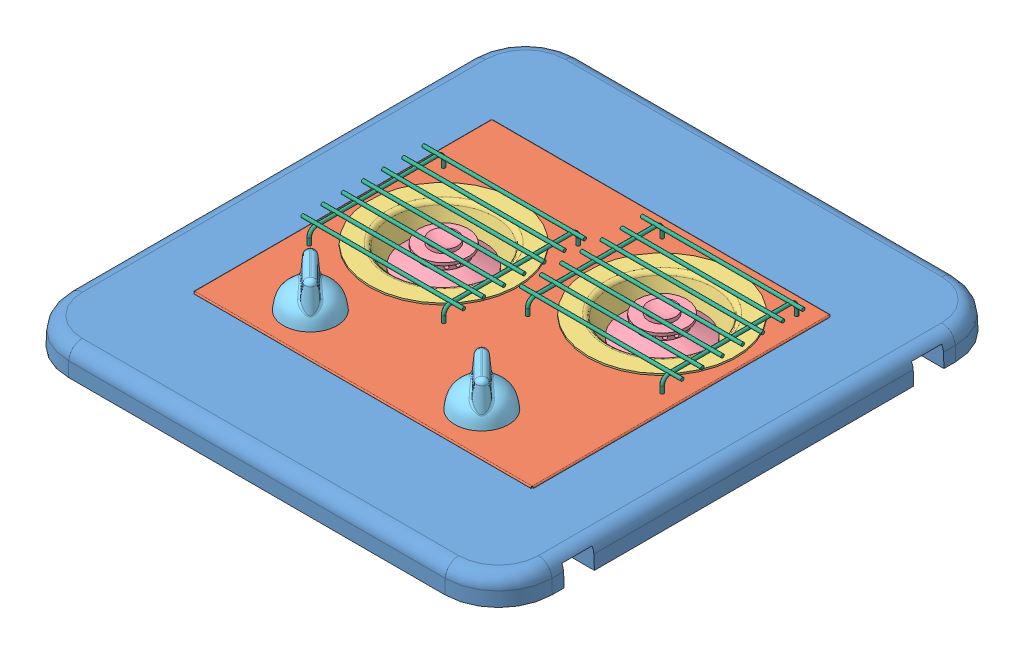
SolidWorks assembly side_table_shelf_and_burners, configuration Default. Lengths in mm.
Overall size (457.2 166.61 482.6).
18 component instances, 10 part files, 5 mates.
Components (placement in the parent):
- side_table_shelf_for_burner-1: side_table_shelf_for_burner [Default] at origin
- double_range_burner-1: double_range_burner [Reduced] at (-1.5875 27.5336 -1.5875) x (-1 0 0) z (0 0 1) size (320.68 166.61 313.56)
  - range_burner_insert-1: range_burner_insert [Default] at origin
  - range_burner-1: range_burner [Default] at (-80.9625 38.1 -60.8457) x (-1 0 0) z (0 0 1) size (139.7 50.8 139.7)
    - range_burner_bowl-1: range_burner_bowl [Default] at origin
    - range_burner_head-1: range_burner_head [Default] at (0 17.8134 0) x (0.999007 0 -0.04455) z (0.04455 0 0.999007)
  - Lofted Control Knob-1: Lofted Control Knob [Default] at (80.9625 -8.4351 109.5375) x (0.707107 0 -0.707107) z (-0.707107 0 -0.707107)
  - range_burner_grill-1: range_burner_grill [Default] at (-17.4625 -12.7 -60.8457) x (0 0 1) z (1 0 0)
  - range_burner-2: range_burner [Default] at (79.8957 38.1 -15.3543) x (-1 0 0) z (0 0 1) size (139.7 50.8 139.7)
    - range_burner_bowl-1: range_burner_bowl [Default] at origin
    - range_burner_head-1: range_burner_head [Default] at (0 17.8134 0) x (0.999007 0 -0.04455) z (0.04455 0 0.999007)
  - range_burner_grill-2: range_burner_grill [Default] at (143.3957 -12.7 -15.3543) x (0 0 1) z (1 0 0)
  - range_burner_valve-1: range_burner_valve [Default] at (-80.9625 29.591 109.5375) x (0 -1 0) z (1 0 0)
  - Lofted Control Knob-2: Lofted Control Knob [Default] at (-80.9625 -8.4351 109.5375) x (0.707107 0 -0.707107) z (-0.707107 0 -0.707107)
  - range_burner_valve-2: range_burner_valve [Default] at (79.8957 29.591 109.5375) x (0 -1 0) z (1 0 0)
  - range_burner_valve_feed-1: range_burner_valve_feed [Default] at (-0.4953 89.916 109.5375)
  - short_burner_tube-1: short_burner_tube [Default] at (79.8957 45.6866 -15.3543) x (-0.999007 0 -0.04455) z (0 1 0)
  - long_burner_tube-1: long_burner_tube [Default] at (-80.9625 45.6866 -60.8457) x (-0.999007 0 -0.04455) z (0 1 0)
Mates (geometry in assembly coordinates):
- Coincident23: coincident anti-aligned: plane of side_table_shelf_for_burner-1 through (-177.8 25.4 -190.5) normal (0 1 0); plane of double_range_burner-1/range_burner_insert-1 through (-156.6291 25.4 -1.5875) normal (0 -1 0)
- Coincident24: coincident anti-aligned: plane of side_table_shelf_for_burner-1 through (-152.4 0 133.35) normal (1 0 0); plane of double_range_burner-1/range_burner_insert-1 through (-152.4 12.7 117.475) normal (-1 0 0)
- Coincident25: coincident anti-aligned: plane of side_table_shelf_for_burner-1 through (-152.4 0 -133.35) normal (0 0 1); plane of double_range_burner-1/range_burner_insert-1 through (-151.6929 25.4 -133.35) normal (0 0 -1)
- Coincident26: coincident anti-aligned: plane of side_table_shelf_for_burner-1 through (-152.4 0 -133.35) normal (0 0 1); plane of double_range_burner-1/range_burner_insert-1 through (49.2125 25.4 130.175) normal (0 0 1)
- Coincident27: coincident anti-aligned: plane of side_table_shelf_for_burner-1 through (-152.4 0 133.35) normal (1 0 0); plane of double_range_burner-1/range_burner_insert-1 through (149.225 12.7 -120.65) normal (1 0 0)
